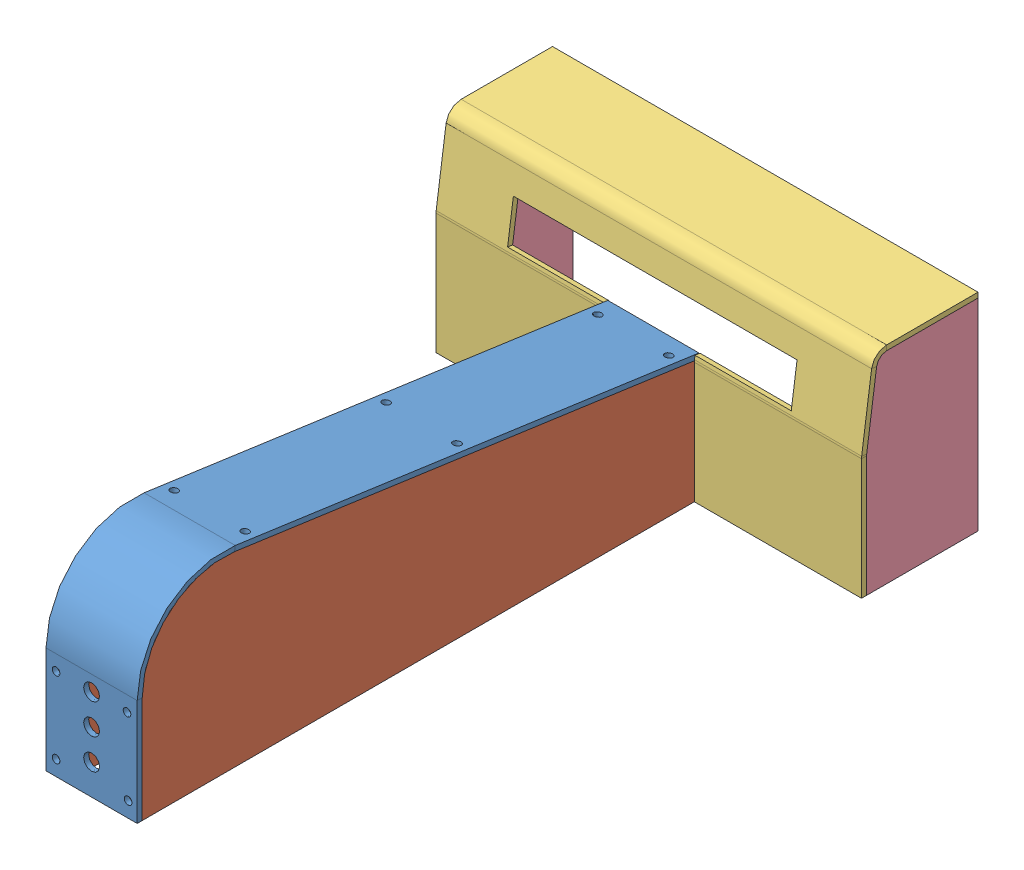
SolidWorks assembly CHARGING, CHASSIS, TOP ASSY, configuration Default. Lengths in mm.
Overall size (133.35 64.84 211.14).
7 component instances, 5 part files, 21 mates.
Components (placement in the parent):
- CHARGING, PLATE, Cover-1: CHARGING, PLATE, Cover [Default] at origin size (28.57 60.36 176.07)
- CHARGING, PLATE, Side-4: CHARGING, PLATE, Side [Default] at (-11.1125 0 0) size (6.35 58.77 174.27)
- CHARGING, PLATE, Side-5: CHARGING, PLATE, Side [Default] at (11.1125 0 0) size (6.35 58.77 174.27)
- CHARGING, PLATE, Charging Bay Cover-1: CHARGING, PLATE, Charging Bay Cover [Default] at origin size (133.35 64.84 36.51)
- CHARGING, PLATE, Bay Side-1: CHARGING, PLATE, Bay Side [Default] at (63.5 0 0) size (6.35 63.25 34.92)
- CHARGING, PLATE, Bay Side-2: CHARGING, PLATE, Bay Side [Default] at (-63.5 0 0) size (6.35 63.25 34.92)
- CHARGING, PLATE, Rear Base-1: CHARGING, PLATE, Rear Base [Default] at (0 0 -192.0875) size (120.65 3.17 209.55)
Mates (geometry in assembly coordinates):
- Coincident6: coincident aligned: plane of CHARGING, PLATE, Cover-1 through (0 0 0) normal (0 0 1); plane of assembly through (0 0 0) normal (0 0 1)
- Coincident7: coincident aligned: plane of CHARGING, PLATE, Cover-1 through (0 0 0) normal (0 1 0); plane of assembly through (0 0 0) normal (0 1 0)
- Coincident8: coincident aligned: plane of CHARGING, PLATE, Cover-1 through (0 0 0) normal (1 0 0); plane of assembly through (0 0 0) normal (1 0 0)
- Coincident9: coincident aligned: plane of CHARGING, PLATE, Side-4 through (-11.1125 0 0) normal (0 0 1); plane of assembly through (0 0 0) normal (0 0 1)
- Coincident10: coincident aligned: plane of CHARGING, PLATE, Side-4 through (-11.1125 0 0) normal (0 1 0); plane of assembly through (0 0 0) normal (0 1 0)
- Coincident11: coincident aligned: plane of CHARGING, PLATE, Side-5 through (11.1125 0 0) normal (0 0 1); plane of assembly through (0 0 0) normal (0 0 1)
- Coincident12: coincident aligned: plane of assembly through (0 0 0) normal (0 1 0); plane of CHARGING, PLATE, Side-5 through (11.1125 0 0) normal (0 1 0)
- Symmetric1: symmetric anti-aligned: plane of CHARGING, PLATE, Side-4 through (-11.1125 0 0) normal (1 0 0); plane of CHARGING, PLATE, Side-5 through (11.1125 0 0) normal (1 0 0); plane of assembly through (0 0 0) normal (1 0 0)
- Coincident14: coincident aligned: plane of CHARGING, PLATE, Cover-1 through (14.2875 33.372 -25.4) normal (1 0 0); plane of CHARGING, PLATE, Side-5 through (14.2875 33.372 -25.4) normal (1 0 0)
- Coincident15: coincident aligned: plane of CHARGING, PLATE, Charging Bay Cover-1 through (0 0 0) normal (1 0 0); plane of assembly through (0 0 0) normal (1 0 0)
- Coincident16: coincident aligned: plane of CHARGING, PLATE, Charging Bay Cover-1 through (0 0 0) normal (0 1 0); plane of assembly through (0 0 0) normal (0 1 0)
- Coincident17: coincident aligned: plane of CHARGING, PLATE, Charging Bay Cover-1 through (0 0 0) normal (0 0 1); plane of assembly through (0 0 0) normal (0 0 1)
- Symmetric2: symmetric aligned: plane of CHARGING, PLATE, Bay Side-1 through (60.325 60.0778 -180.92) normal (-1 0 0); plane of CHARGING, PLATE, Bay Side-2 through (-60.325 60.0778 -180.92) normal (1 0 0); plane of assembly through (0 0 0) normal (1 0 0)
- Coincident18: coincident aligned: plane of CHARGING, PLATE, Bay Side-2 through (-63.5 0 0) normal (0 1 0); plane of assembly through (0 0 0) normal (0 1 0)
- Coincident19: coincident aligned: plane of CHARGING, PLATE, Bay Side-1 through (63.5 0 0) normal (0 1 0); plane of assembly through (0 0 0) normal (0 1 0)
- Coincident20: coincident aligned: plane of CHARGING, PLATE, Bay Side-1 through (63.5 0 0) normal (0 0 1); plane of assembly through (0 0 0) normal (0 0 1)
- Coincident21: coincident aligned: plane of CHARGING, PLATE, Bay Side-2 through (-63.5 0 0) normal (0 0 1); plane of assembly through (0 0 0) normal (0 0 1)
- Coincident22: coincident aligned: plane of CHARGING, PLATE, Charging Bay Cover-1 through (66.675 37.878 -177.8) normal (1 0 0); plane of CHARGING, PLATE, Bay Side-1 through (66.675 60.0778 -180.92) normal (1 0 0)
- Coincident23: coincident aligned: plane of CHARGING, PLATE, Bay Side-1 through (66.675 0 -174.625) normal (0 -1 0); plane of CHARGING, PLATE, Rear Base-1 through (60.325 0 -209.55) normal (0 -1 0)
- Coincident25: coincident aligned: plane of CHARGING, PLATE, Bay Side-1 through (66.675 0 -209.55) normal (0 0 -1); plane of CHARGING, PLATE, Rear Base-1 through (-60.325 3.175 -209.55) normal (0 0 -1)
- Width1: width: plane of CHARGING, PLATE, Rear Base-1 through (-60.325 3.175 -174.625) normal (-1 0 0); plane of CHARGING, PLATE, Rear Base-1 through (60.325 3.175 -174.625) normal (1 0 0); plane of CHARGING, PLATE, Bay Side-1 through (60.325 60.0778 -180.92) normal (-1 0 0); plane of CHARGING, PLATE, Bay Side-2 through (-60.325 60.0778 -180.92) normal (1 0 0)
